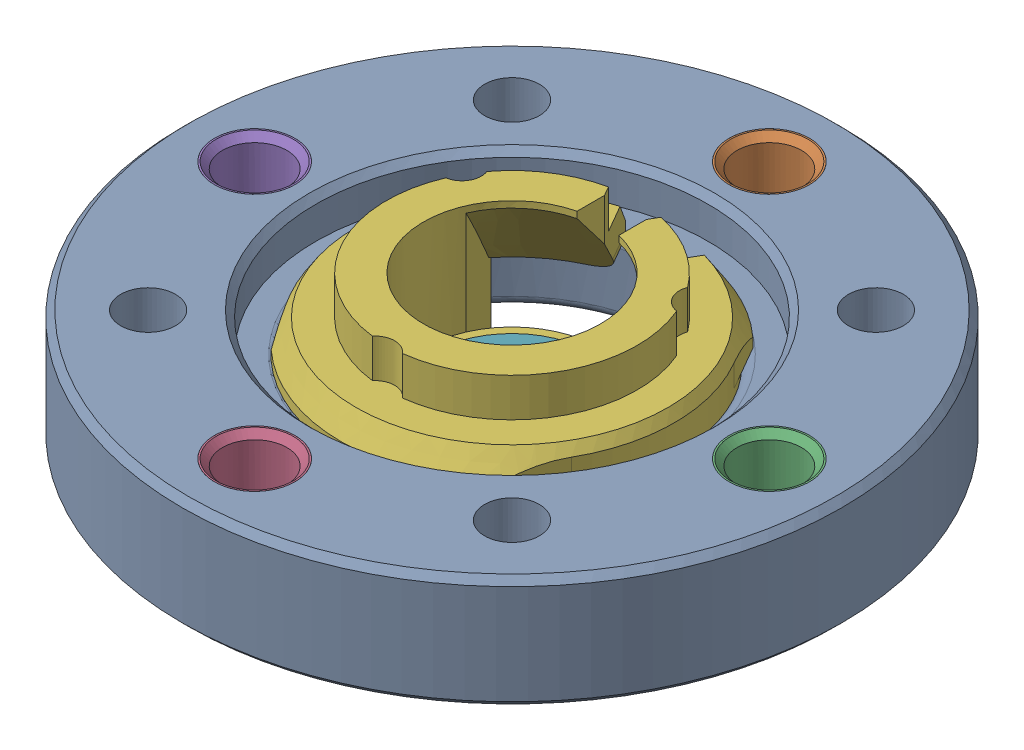
SolidWorks assembly M_DC11_A01_IDLER_ASM, configuration Default. Lengths in mm.
Overall size (20.5 8.4 20.5).
7 component instances, 4 part files, 0 mates.
Components (placement in the parent):
- M_DC11_A01_IDLER_1-1: M_DC11_A01_IDLER_1 [Default] at origin size (20.5 3.5 20.5)
- DC11_A01_HORN_INSERT_1-1: DC11_A01_HORN_INSERT_1 [Default] at (0 0 -8) x (-1 0 0) z (0 0 1) size (2.97 3.5 2.97)
- DC11_A01_HORN_INSERT_1-2: DC11_A01_HORN_INSERT_1 [Default] at (8 0 0) x (-1 0 0) z (0 0 1) size (2.97 3.5 2.97)
- DC11_A01_HORN_INSERT_1-3: DC11_A01_HORN_INSERT_1 [Default] at (0 0 8) x (-1 0 0) z (0 0 1) size (2.97 3.5 2.97)
- DC11_A01_HORN_INSERT_1-4: DC11_A01_HORN_INSERT_1 [Default] at (-8 0 0) x (-1 0 0) z (0 0 1) size (2.97 3.5 2.97)
- M_DC11_A01_IDLER_CAP_1-1: M_DC11_A01_IDLER_CAP_1 [Default] at (0 -0.2 0) x (1 0 0) z (0 0 -1) size (10.1 5.2 10.37)
- DC11_A01_IDLER_SCREW-1: DC11_A01_IDLER_SCREW [Default] at (0 -3.9 0) size (5 5 5)
